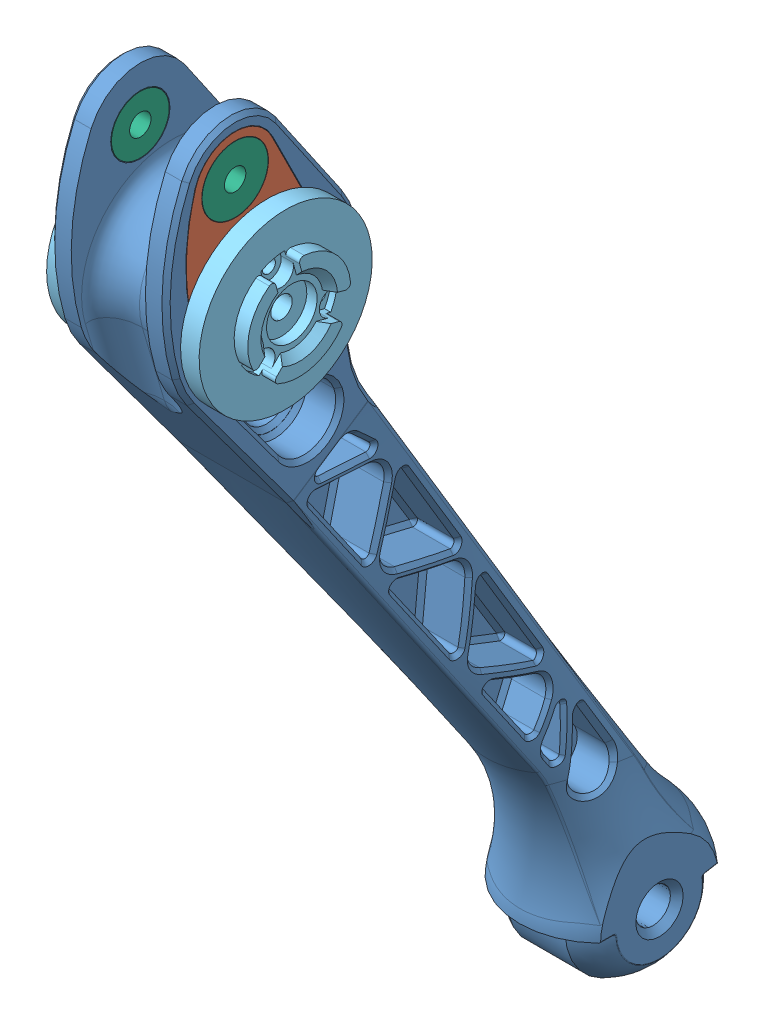
SolidWorks assembly KFE, configuration 默认. Lengths in mm.
Overall size (43.6 233.87 143.58).
8 component instances, 6 part files, 22 mates.
Components (placement in the parent):
- 小腿一体加工-1: 小腿一体加工 [默认] at (-17.5988 -83.2085 179.0486) size (36.85 233.87 139.43)
- 加强板-1: 加强板 [默认] at (-3.5988 118.9744 286.8132) x (-1 0 0) z (0 0 -1) size (3 54.98 35.58)
- 加强板neice-1: 加强板neice [默认] at (-28.5988 118.9744 286.8132) x (-1 0 0) z (0 0 -1) size (3 54.98 35.58)
- 六角钢柱-2: 六角钢柱 [默认] at (-29.8488 89.9966 279.0486) x (0 0.188716 -0.982032) z (0 -0.982032 -0.188716) size (7.62 25 6)
- 肘部转轴大-2: 肘部转轴大 [默认] at (-31.5988 89.9966 279.0486) x (0 1 0) z (0 0 1) size (42 21.6 42)
- 肘部转轴大-3: 肘部转轴大 [默认] at (-3.5988 89.9966 279.0486) x (0 -0.866025 0.5) z (0 0.5 0.866025) size (42 21.6 42)
- 5-14-5挡边轴承-1: 5-14-5挡边轴承 [默认] at (-26.5988 118.9744 286.8132) x (0 -0.810786 0.585342) z (0 -0.585342 -0.810786) size (16 5 16)
- 5-14-5挡边轴承-2: 5-14-5挡边轴承 [默认] at (-8.5988 118.9744 286.8132) x (0 -0.961487 -0.274849) z (0 -0.274849 0.961487) size (16 5 16)
Mates (geometry in assembly coordinates):
- 重合2: coincident anti-aligned: plane of 小腿一体加工-1 through (-28.5988 92.5957 273.4748) normal (-1 0 0); plane of 加强板neice-1 through (-28.5988 118.9744 286.8132) normal (1 0 0)
- 同心2: concentric aligned: cylinder of 小腿一体加工-1 through (-31.5988 87.4084 269.3894) axis (1 0 0) radius 2.705; cylinder of 加强板neice-1 through (-38.5988 87.4084 269.3894) axis (1 0 0) radius 2.55
- 同心3: concentric aligned: cylinder of 小腿一体加工-1 through (-31.5988 99.6559 281.6368) axis (1 0 0) radius 2.705; cylinder of 加强板neice-1 through (-38.5988 99.6559 281.6368) axis (1 0 0) radius 2.55
- 重合3: coincident anti-aligned: plane of 小腿一体加工-1 through (-6.5988 92.5957 273.4748) normal (1 0 0); plane of 加强板-1 through (-6.5988 118.9744 286.8132) normal (-1 0 0)
- 同心4: concentric aligned: cylinder of 小腿一体加工-1 through (-31.5988 99.6559 281.6368) axis (1 0 0) radius 2.705; cylinder of 加强板-1 through (-13.5988 99.6559 281.6368) axis (1 0 0) radius 2.55
- 同心5: concentric aligned: cylinder of 小腿一体加工-1 through (-31.5988 87.4084 269.3894) axis (1 0 0) radius 2.705; cylinder of 加强板-1 through (-13.5988 87.4084 269.3894) axis (1 0 0) radius 2.55
- 同心6: concentric anti-aligned: cylinder of 小腿一体加工-1 through (-31.5988 87.4084 269.3894) axis (1 0 0) radius 2.705; cylinder of 六角钢柱-1 through (-3.5988 87.4084 269.3894) axis (-1 0 0) radius 2
- 重合4: coincident aligned: circle of 小腿一体加工-1; plane of 六角钢柱-1 through (-28.5988 87.4084 269.3894) normal (-1 0 0)
- 同心8: concentric anti-aligned: cylinder of 小腿一体加工-1 through (-31.5988 99.6559 281.6368) axis (1 0 0) radius 2.705; cylinder of 六角钢柱-3 through (-3.5988 99.6559 281.6368) axis (-1 0 0) radius 2
- 重合6: coincident anti-aligned: circle of 加强板neice-1; plane of 六角钢柱-3 through (-28.5988 99.6559 281.6368) normal (-1 0 0)
- 同心9: concentric anti-aligned: cylinder of 加强板neice-1 through (-38.5988 87.4084 269.3894) axis (1 0 0) radius 2.55; cylinder of 肘部转轴大-2 through (-22.5988 87.4084 269.3894) axis (-1 0 0) radius 1.6
- 同心10: concentric aligned: cylinder of 小腿一体加工-1 through (-3.5988 89.9966 279.0486) axis (-1 0 0) radius 5.075; cylinder of 肘部转轴大-2 through (-17.7988 89.9966 279.0486) axis (-1 0 0) radius 4.9
- 重合7: coincident anti-aligned: plane of 加强板neice-1 through (-31.5988 118.9744 286.8132) normal (-1 0 0); plane of 肘部转轴大-2 through (-31.5988 89.9966 279.0486) normal (1 0 0)
- 同心11: concentric anti-aligned: cylinder of 小腿一体加工-1 through (-3.5988 89.9966 279.0486) axis (-1 0 0) radius 5.075; cylinder of 肘部转轴大-3 through (-17.3988 89.9966 279.0486) axis (1 0 0) radius 4.9
- 同心12: concentric anti-aligned: cylinder of 六角钢柱-1 through (-3.5988 87.4084 269.3894) axis (-1 0 0) radius 2; cylinder of 肘部转轴大-3 through (-12.5988 87.4084 269.3894) axis (1 0 0) radius 1.6
- 重合8: coincident anti-aligned: plane of 加强板-1 through (-3.5988 118.9744 286.8132) normal (1 0 0); plane of 肘部转轴大-3 through (-3.5988 89.9966 279.0486) normal (-1 0 0)
- 同心13: concentric aligned: cylinder of 加强板neice-1 through (-38.5988 118.9744 286.8132) axis (1 0 0) radius 7.1; cylinder of 5-14-5挡边轴承-1 through (-31.5988 118.9744 286.8132) axis (1 0 0) radius 7
- 重合9: coincident anti-aligned: plane of 加强板neice-1 through (-30.5988 118.9744 286.8132) normal (-1 0 0); plane of 5-14-5挡边轴承-1 through (-30.5988 118.9744 286.8132) normal (1 0 0)
- 同心14: concentric anti-aligned: cylinder of 加强板-1 through (-13.5988 118.9744 286.8132) axis (1 0 0) radius 7.1; cylinder of 5-14-5挡边轴承-2 through (-3.5988 118.9744 286.8132) axis (-1 0 0) radius 7
- 重合10: coincident anti-aligned: plane of 加强板-1 through (-4.5988 118.9744 286.8132) normal (1 0 0); plane of 5-14-5挡边轴承-2 through (-4.5988 118.9744 286.8132) normal (-1 0 0)
- 同心15: concentric aligned: cylinder of 小腿一体加工-1 through (-3.5988 89.9966 279.0486) axis (-1 0 0) radius 23; cylinder of 六角钢柱-2 through (-4.8488 89.9966 279.0486) axis (-1 0 0) radius 2
- 重合11: coincident aligned: plane of 六角钢柱-2 through (-4.8488 89.9966 279.0486) normal (1 0 0); circle of 肘部转轴大-3
